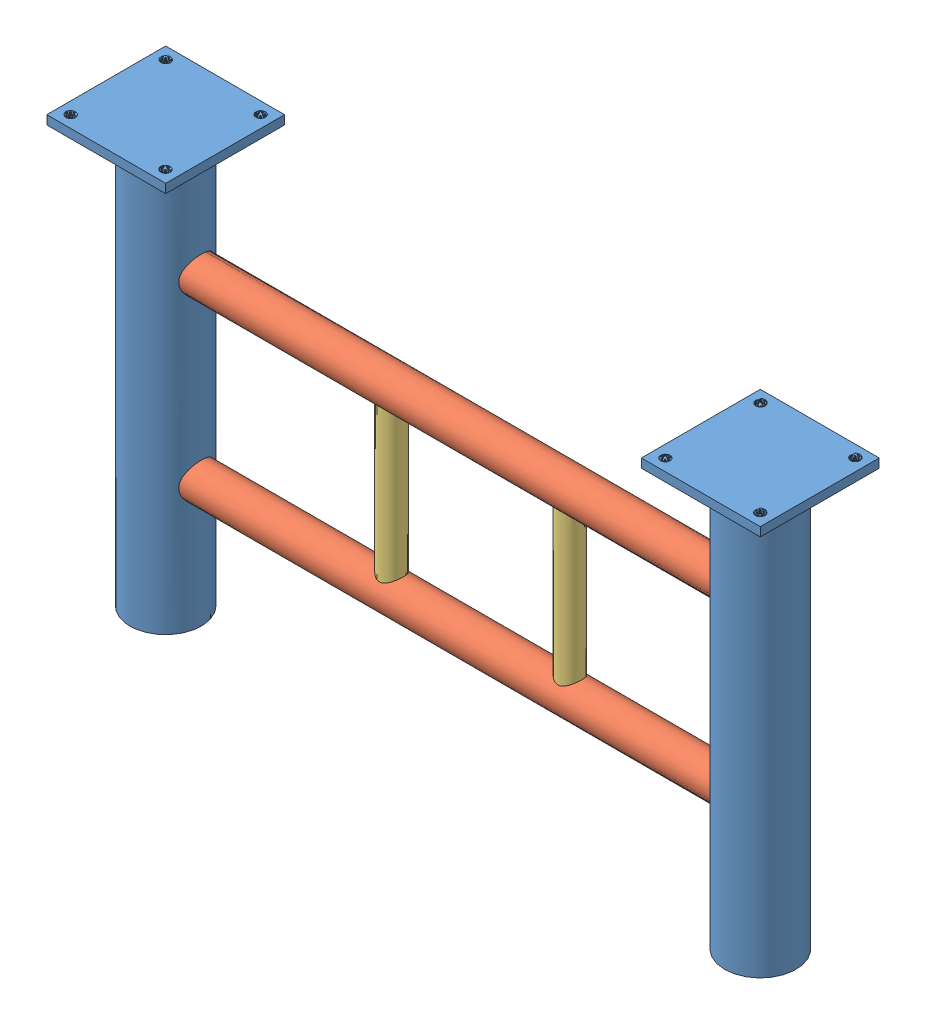
SolidWorks assembly Lam-300120566-ProJ-SubAssembly1, configuration Default. Lengths in mm.
Overall size (304.8 181.92 50.8).
6 component instances, 3 part files, 12 mates.
Components (placement in the parent):
- Lam-300120566-Proj-Part2-1: Lam-300120566-Proj-Part2 [Default] at (4.3611 13.5942 166.3327) size (50.8 181.92 50.8)
- Lam-300120566-Proj-Part3-1: Lam-300120566-Proj-Part3 [Default] at (258.3611 143.6041 166.3327) x (0 1 0) z (0 0 1) size (15.24 261.62 15.24)
- Lam-300120566-Proj-Part3-2: Lam-300120566-Proj-Part3 [Default] at (258.3611 67.4041 166.3327) x (0 -1 0) z (0 0 -1) size (15.24 261.62 15.24)
- Lam-300120566-Proj-Part2-3: Lam-300120566-Proj-Part2 [Default] at (258.3611 13.5942 166.3327) x (-1 0 0) z (0 0 -1) size (50.8 181.92 50.8)
- Lam-300120566-Proj-Part4-1: Lam-300120566-Proj-Part4 [Default] at (100.8239 67.4041 166.3327) x (0.999994 0 0.003318) z (-0.003318 0 0.999994) size (10.16 76.2 10.16)
- Lam-300120566-Proj-Part4-2: Lam-300120566-Proj-Part4 [Default] at (177.0239 67.4041 166.3327) size (10.16 76.2 10.16)
Mates (geometry in assembly coordinates):
- Coincident1: coincident anti-aligned: plane of Lam-300120566-Proj-Part2-1 through (4.3611 143.6041 166.3327) normal (1 0 0); circle of Lam-300120566-Proj-Part3-1
- Concentric1: concentric anti-aligned: cylinder of Lam-300120566-Proj-Part2-1 through (207.5611 143.6041 166.3327) axis (-1 0 0) radius 7.62; cylinder of Lam-300120566-Proj-Part3-1 through (4.3611 143.6041 166.3327) axis (1 0 0) radius 7.62
- Coincident2: coincident anti-aligned: circle of Lam-300120566-Proj-Part2-1; circle of Lam-300120566-Proj-Part3-2
- Coincident5: coincident aligned: circle of Lam-300120566-Proj-Part3-1; plane of Lam-300120566-Proj-Part2-3 through (258.3611 143.6041 166.3327) normal (-1 0 0)
- Concentric3: concentric aligned: cylinder of Lam-300120566-Proj-Part3-1 through (4.3611 143.6041 166.3327) axis (1 0 0) radius 7.62; cylinder of Lam-300120566-Proj-Part2-3 through (55.1611 143.6041 166.3327) axis (1 0 0) radius 7.62
- Coincident6: coincident anti-aligned: plane of Lam-300120566-Proj-Part3-2 through (258.3611 67.4041 166.3327) normal (1 0 0); plane of Lam-300120566-Proj-Part2-3 through (258.3611 67.4041 166.3327) normal (-1 0 0)
- Concentric4: concentric aligned: cylinder of Lam-300120566-Proj-Part3-2 through (4.3611 67.4041 166.3327) axis (1 0 0) radius 7.62; cylinder of Lam-300120566-Proj-Part2-3 through (55.1611 67.4041 166.3327) axis (1 0 0) radius 7.62
- Coincident11: coincident anti-aligned: plane of Lam-300120566-Proj-Part3-1 through (100.8239 143.6041 166.3327) normal (0 -1 0); plane of Lam-300120566-Proj-Part4-1 through (100.8239 143.6041 166.3327) normal (0 1 0)
- Concentric9: concentric anti-aligned: cylinder of Lam-300120566-Proj-Part3-1 through (100.8239 135.9841 166.3327) axis (0 1 0) radius 5.08; cylinder of Lam-300120566-Proj-Part4-1 through (100.8239 143.6041 166.3327) axis (0 -1 0) radius 5.08
- Coincident12: coincident anti-aligned: plane of Lam-300120566-Proj-Part3-2 through (100.8239 67.4041 166.3327) normal (0 1 0); plane of Lam-300120566-Proj-Part4-1 through (100.8239 67.4041 166.3327) normal (0 -1 0)
- Coincident13: coincident anti-aligned: plane of Lam-300120566-Proj-Part3-1 through (177.0239 143.6041 166.3327) normal (0 -1 0); plane of Lam-300120566-Proj-Part4-2 through (177.0239 143.6041 166.3327) normal (0 1 0)
- Concentric10: concentric anti-aligned: cylinder of Lam-300120566-Proj-Part3-1 through (177.0239 135.9841 166.3327) axis (0 1 0) radius 5.08; cylinder of Lam-300120566-Proj-Part4-2 through (177.0239 143.6041 166.3327) axis (0 -1 0) radius 5.08
